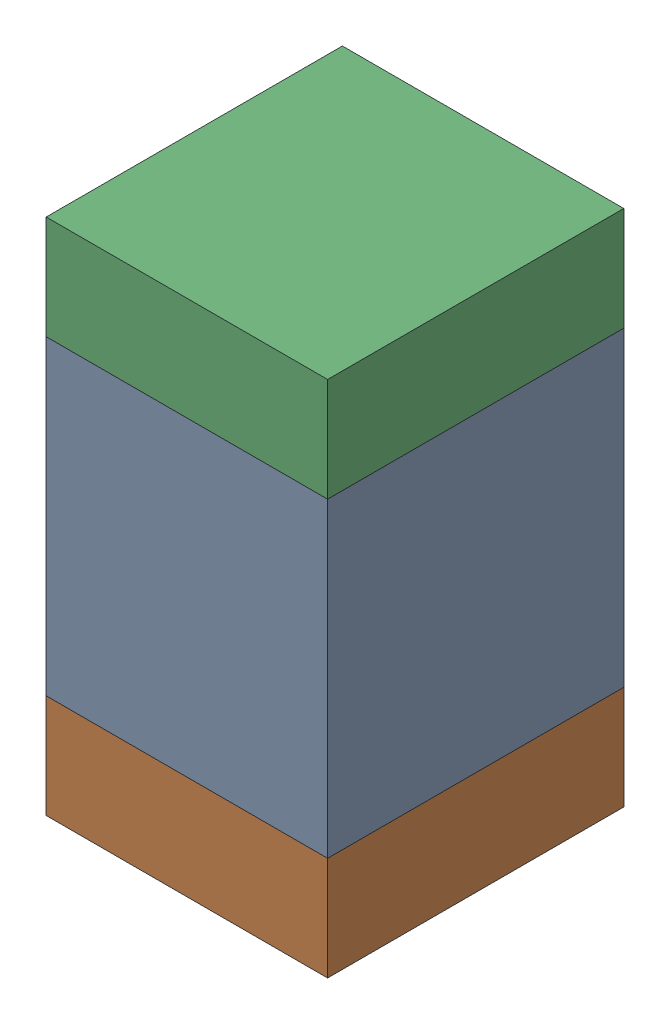
SolidWorks assembly C420PCB, configuration Default. Lengths in mm.
Overall size (0.95 1.75 1).
6 component instances, 2 part files, 0 mates.
Components (placement in the parent):
- 761616384-1: 761616384 [Default] at (114.6 111.9 -2.6638) size (0.95 1.05 1)
  - Extruded_5-1: Extruded_5 [Default] at origin size (0.95 1.05 1)
- 761616520-1: 761616520 [Default] at (114.6 111.2 -2.6638) size (0.95 0.35 1)
  - Extruded_6-1: Extruded_6 [Default] at origin size (0.95 0.35 1)
- 761616520-2: 761616520 [Default] at (114.6 112.6 -2.6638) size (0.95 0.35 1)
  - Extruded_6-1: Extruded_6 [Default] at origin size (0.95 0.35 1)
